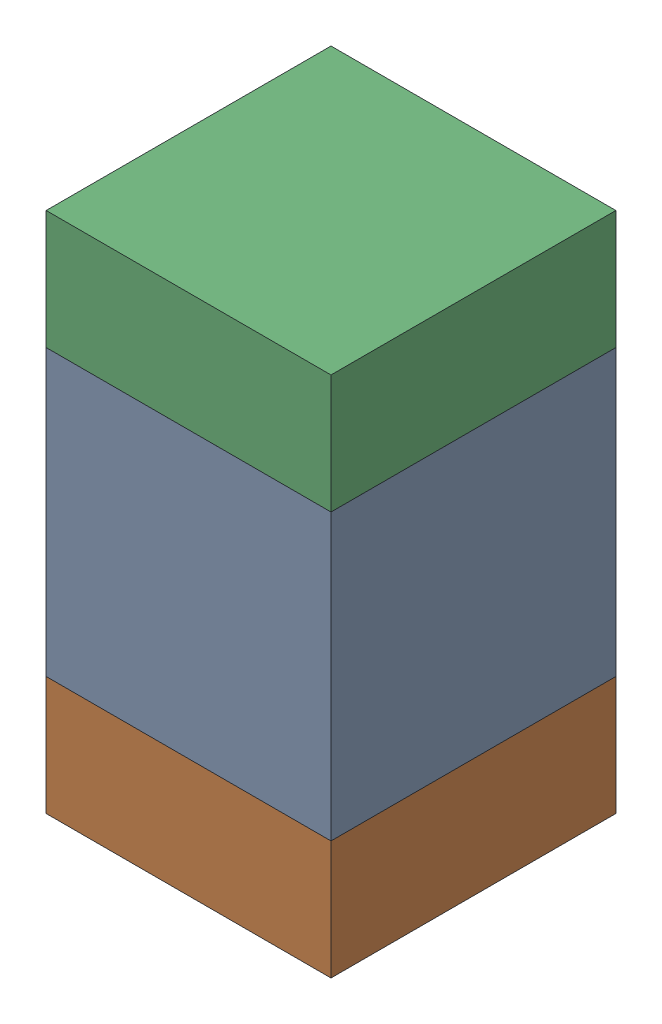
SolidWorks assembly C500_2PCB, configuration Default. Lengths in mm.
Overall size (0.6 1.1 0.6).
6 component instances, 2 part files, 0 mates.
Components (placement in the parent):
- 761606048-1: 761606048 [Default] at (156 87.6 0) size (0.6 0.6 0.6)
  - Extruded_9-1: Extruded_9 [Default] at origin size (0.6 0.6 0.6)
- 854785296-1: 854785296 [Default] at (156 87.175 0) size (0.6 0.25 0.6)
  - Extruded_10-1: Extruded_10 [Default] at origin size (0.6 0.25 0.6)
- 854785296-2: 854785296 [Default] at (156 88.025 0) size (0.6 0.25 0.6)
  - Extruded_10-1: Extruded_10 [Default] at origin size (0.6 0.25 0.6)
